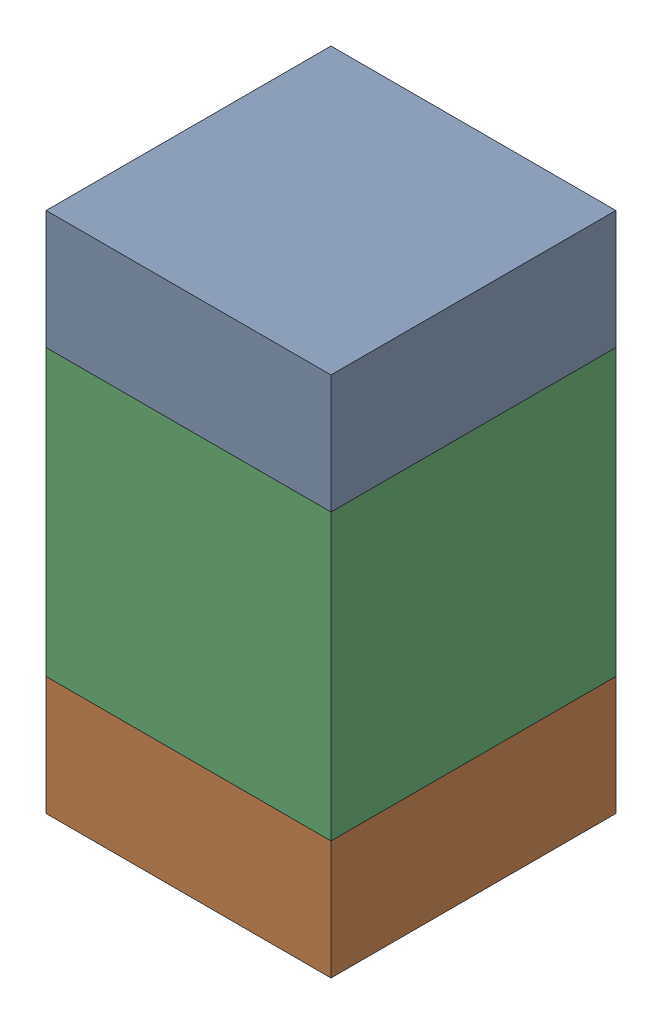
SolidWorks assembly C106_1PCB, configuration Default. Lengths in mm.
Overall size (0.6 1.1 0.6).
6 component instances, 2 part files, 0 mates.
Components (placement in the parent):
- 854785296-1: 854785296 [Default] at (103.3 106.625 0) size (0.6 0.25 0.6)
  - Extruded_10-1: Extruded_10 [Default] at origin size (0.6 0.25 0.6)
- 854785296-2: 854785296 [Default] at (103.3 105.775 0) size (0.6 0.25 0.6)
  - Extruded_10-1: Extruded_10 [Default] at origin size (0.6 0.25 0.6)
- 761606048-1: 761606048 [Default] at (103.3 106.2 0) size (0.6 0.6 0.6)
  - Extruded_9-1: Extruded_9 [Default] at origin size (0.6 0.6 0.6)
